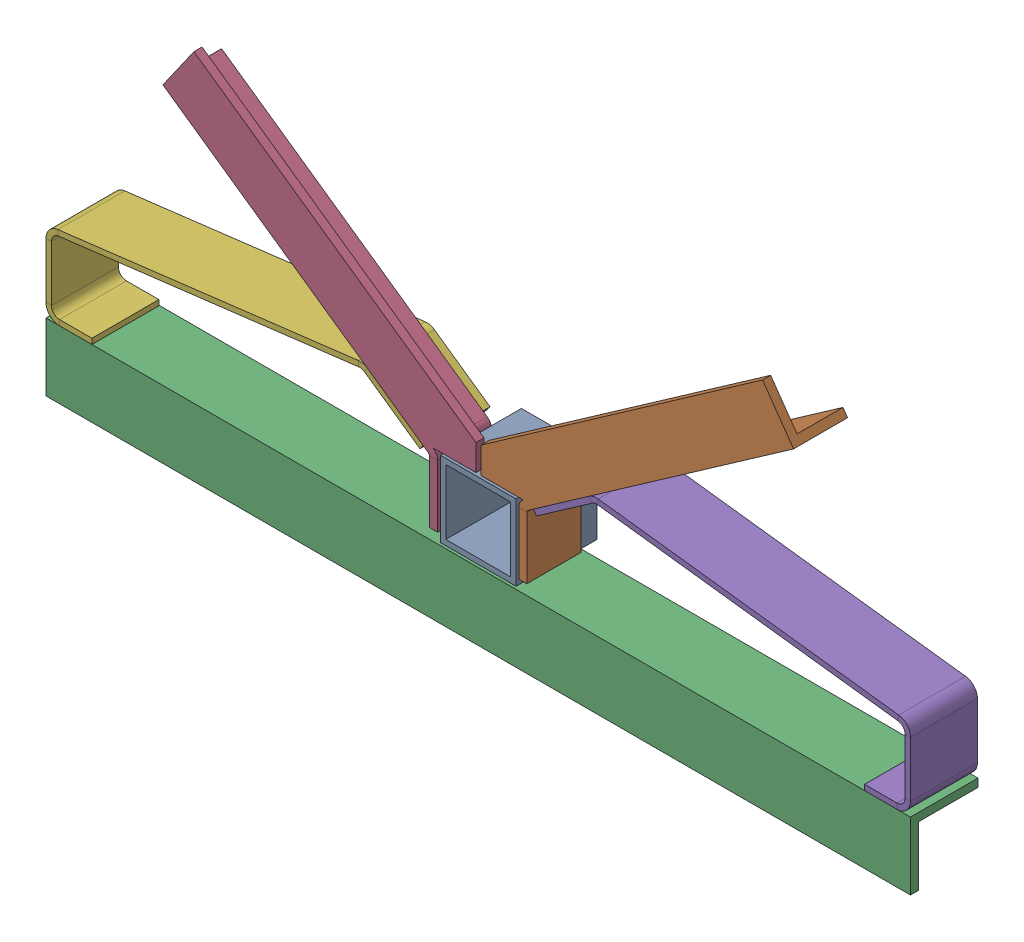
SolidWorks assembly СошкиСб, configuration По умолчанию. Lengths in mm.
Overall size (326.12 137.75 30).
6 component instances, 5 part files, 12 mates.
Components (placement in the parent):
- Втулка28-1: Втулка28 [По умолчанию] at (0 0 30) x (1 0 0) z (0 1 0) size (28 30 28)
- У20_140-1: У20_140 [По умолчанию] at (18.4264 12.5425 30) x (0.819152 0.573576 0) z (0 0 1) size (136.42 39.2 20)
- У25_240-1: У25_240 [По умолчанию] at (160 -15 30) x (-1 0 0) z (0 0 1) size (320 25 25)
- У20_140L-1: У20_140L [По умолчанию] at (-116.7247 81.3717 30) x (0.819152 -0.573576 0) z (0 0 1) size (136.42 39.2 20)
- Ребро-1: Ребро [По умолчанию] at (44.2004 27.2034 5.2119) x (0.992546 -0.121869 0) z (0 0 -1) size (141.49 31.85 24.79)
- Ребро-2: Ребро [По умолчанию] at (-44.2004 27.2034 30) x (-0.992546 -0.121869 0) z (0 0 1) size (141.49 31.85 24.79)
Mates (geometry in assembly coordinates):
- Расстояние4: distance = 15 mm aligned: plane of У25_240-1 through (-160 -15 30) normal (0 1 0)
- Расстояние5: distance = 30 mm aligned: plane of У25_240-1 through (-160 -40 30) normal (0 0 1)
- Совпадение11: coincident: point of У25_240-1
- Расстояние6: distance = 15 mm anti-aligned: plane of У20_140-1 through (15 12.244 30) normal (-1 0 0)
- Расстояние8: distance = 30 mm aligned: plane of У20_140-1 through (105.2531 97.7548 30) normal (0 0 1)
- Расстояние9: distance = 15 mm aligned: plane of У20_140L-1 through (-15 81.0731 30) normal (1 0 0); plane of assembly through (0 0 0) normal (1 0 0)
- Совпадение17: coincident aligned: plane of У20_140-1 through (15 -11.1943 10) normal (0 -1 0); plane of У20_140L-1 through (-15 -11.1943 30) normal (0 -1 0)
- Совпадение18: coincident aligned: plane of У20_140-1 through (15 -11.1943 30) normal (0 0 1); plane of У20_140L-1 through (-15 12.244 30) normal (0 0 1)
- Расстояние10: distance = 15 mm anti-aligned: plane of У20_140-1 through (16.7057 15 27) normal (0 -1 0)
- Совпадение20: coincident aligned: plane of У25_240-1 through (-160 -40 30) normal (0 0 1); plane of Ребро-1 through (44.4442 29.1885 30) normal (0 0 1)
- Совпадение21: coincident anti-aligned: plane of У25_240-1 through (-160 -15 30) normal (0 1 0); plane of Ребро-1 through (44.2004 -15 5.2119) normal (0 -1 0)
- Совпадение25: coincident aligned: plane of У25_240-1 through (160 -15 30) normal (1 0 0); line of Ребро-1 through (160 -10 30) axis (0 0 -1)
